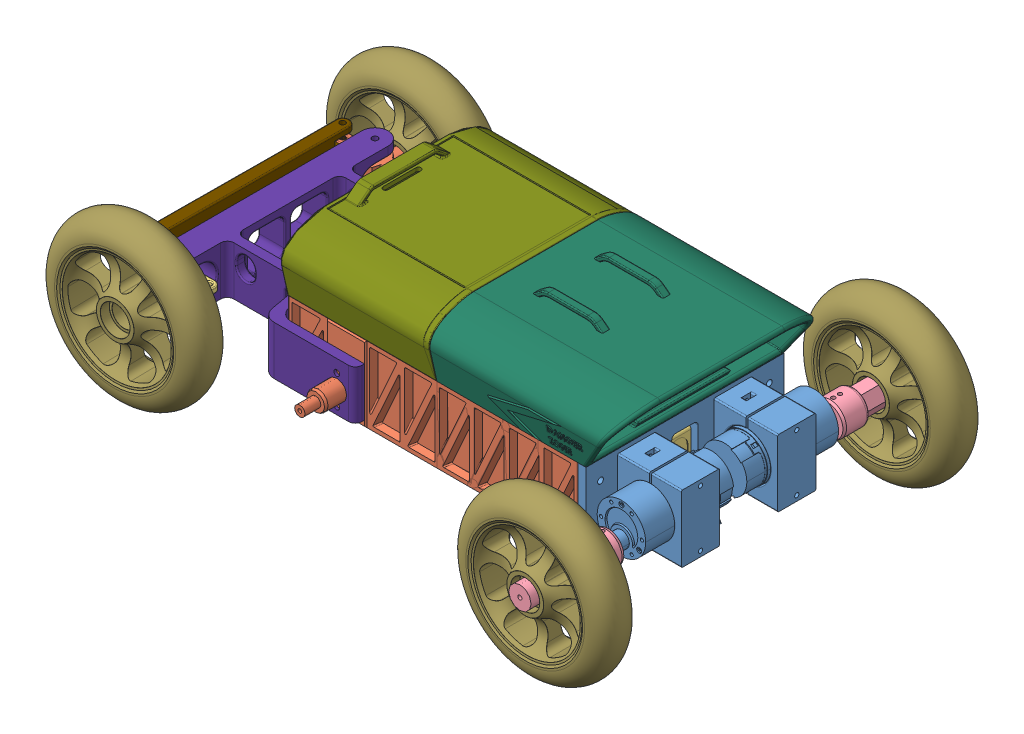
SolidWorks assembly Assem1, configuration Default. Lengths in mm.
Overall size (495.08 171.35 292.11).
38 component instances, 24 part files, 59 mates.
Components (placement in the parent):
- 37D motor clamp-1: 37D motor clamp [Default] at (81 28.5 53.125) size (54.32 57 190.1)
- MainChasis-1: MainChasis [Default] at origin size (220.8 57 222)
- Turnigy_2200mAh_3S_20C_Lipo_Pack-1: Turnigy_2200mAh_3S_20C_Lipo_Pack [Valor predeterminado] at (19.2115 22 -12.0586) size (103 34 24)
- 17HexHub(3.2shaft)-1: 17HexHub(3.2shaft) [Default] at (100.925 21.5 83.05) x (1 0 0) z (0 -1 0) size (25 67 25)
- raspberryPi3B-1: raspberryPi3B [Detailed] at (-91 17 -32.5) x (1 0 0) z (0 1 0) size (87.05 58.5 18.55)
- BTS7960 43A HIGH POWER H BRIDGE MODULE-1: BTS7960 43A HIGH POWER H BRIDGE MODULE [Default] at (35 15 38.7) size (51 42.4 49.96)
  - PCB, BTS7960 43A HIGH POWER H BRIDGE MODULE-1: PCB, BTS7960 43A HIGH POWER H BRIDGE MODULE [Default] at origin size (49.5 1.7 49.8)
  - HEATSINK, BTS7960 43A HIGH POWER H BRIDGE MODULE-1: HEATSINK, BTS7960 43A HIGH POWER H BRIDGE MODULE [Default] at (0 0 2.4) size (51 23 32.02)
  - ALUMINUM ELECTROLYTIC CAPACITOR, 330 uF, BTS7960 43A HIGH POWER H BRIDGE MODULE-1: ALUMINUM ELECTROLYTIC CAPACITOR, 330 uF, BTS7960 43A HIGH POWER H BRIDGE MODULE [Default] at (-10.75 1.8 -19.85) x (0.999469 0 -0.032584) z (0.032584 0 0.999469) size (10.1 18.7 10.1)
  - 8 PIN HEADER, IC, BTS7960 43A HIGH POWER H BRIDGE MODULE-1: 8 PIN HEADER, IC, BTS7960 43A HIGH POWER H BRIDGE MODULE [Default] at (-34.78 4.2 20.29) x (0 0 -1) z (-1 0 0) size (5.08 11.6 10.16)
  - EUROSTYLE TERMINAL BLOCK 2 POS 5.0 MM RA PLUG, BTS7960 43A HIGH POWER H BRIDGE MODULE-1: EUROSTYLE TERMINAL BLOCK 2 POS 5.0 MM RA PLUG, BTS7960 43A HIGH POWER H BRIDGE MODULE [Default] at (0.75 4.2 -6.5) size (10 14.5 10.5)
  - EUROSTYLE TERMINAL BLOCK 2 POS 5.0 MM RA PLUG, BTS7960 43A HIGH POWER H BRIDGE MODULE-2: EUROSTYLE TERMINAL BLOCK 2 POS 5.0 MM RA PLUG, BTS7960 43A HIGH POWER H BRIDGE MODULE [Default] at (10.75 4.2 -6.5) size (10 14.5 10.5)
- BTS7960 43A HIGH POWER H BRIDGE MODULE-2: BTS7960 43A HIGH POWER H BRIDGE MODULE [Default] at (35 15 -41.3) size (51 42.4 49.96)
  - PCB, BTS7960 43A HIGH POWER H BRIDGE MODULE-1: PCB, BTS7960 43A HIGH POWER H BRIDGE MODULE [Default] at origin size (49.5 1.7 49.8)
  - HEATSINK, BTS7960 43A HIGH POWER H BRIDGE MODULE-1: HEATSINK, BTS7960 43A HIGH POWER H BRIDGE MODULE [Default] at (0 0 2.4) size (51 23 32.02)
  - ALUMINUM ELECTROLYTIC CAPACITOR, 330 uF, BTS7960 43A HIGH POWER H BRIDGE MODULE-1: ALUMINUM ELECTROLYTIC CAPACITOR, 330 uF, BTS7960 43A HIGH POWER H BRIDGE MODULE [Default] at (-10.75 1.8 -19.85) x (0.999469 0 -0.032584) z (0.032584 0 0.999469) size (10.1 18.7 10.1)
  - 8 PIN HEADER, IC, BTS7960 43A HIGH POWER H BRIDGE MODULE-1: 8 PIN HEADER, IC, BTS7960 43A HIGH POWER H BRIDGE MODULE [Default] at (-34.78 4.2 20.29) x (0 0 -1) z (-1 0 0) size (5.08 11.6 10.16)
  - EUROSTYLE TERMINAL BLOCK 2 POS 5.0 MM RA PLUG, BTS7960 43A HIGH POWER H BRIDGE MODULE-1: EUROSTYLE TERMINAL BLOCK 2 POS 5.0 MM RA PLUG, BTS7960 43A HIGH POWER H BRIDGE MODULE [Default] at (0.75 4.2 -6.5) size (10 14.5 10.5)
  - EUROSTYLE TERMINAL BLOCK 2 POS 5.0 MM RA PLUG, BTS7960 43A HIGH POWER H BRIDGE MODULE-2: EUROSTYLE TERMINAL BLOCK 2 POS 5.0 MM RA PLUG, BTS7960 43A HIGH POWER H BRIDGE MODULE [Default] at (10.75 4.2 -6.5) size (10 14.5 10.5)
- ArduinoMega-1: ArduinoMega [Default] at (-91.5092 16.651 32.4881) x (0.999999 0 0.00146) z (0 -1 0) size (107.95 53.42 12.95)
- Breadboard^Assem1-1: Breadboard^Assem1 [Default] at (26.7945 10.25 259.5004) x (0 0 -1) z (1 0 0) size (165.5 9.51 56.25) (hidden, virtual)
- SCOOTER WHEEL 120mm 7Rays-1: SCOOTER WHEEL 120mm 7Rays [Default] at (100.925 21.5 131.05) x (0 0 1) z (0.712554 -0.701617 0) size (30.01 120 120)
- SCOOTER WHEEL 120mm 7Rays-2: SCOOTER WHEEL 120mm 7Rays [Default] at (-234.3672 22.1 106.9935) x (0.020413 0 0.999792) z (-0.283759 -0.958878 0.005794) size (30.01 120 120)
- Lid-1: Lid [Default] at (19.5 90 0) x (1 0 0) z (0 0 -1) size (113 40 150) (hidden)
- F9.STEP-1: F9.STEP [Default] at (24.2544 92.7094 -32.1983) x (0 0 -1) z (-1 0 0) size (94.4 26.59 93.93)
  - F9 body.STEP-1: F9 body.STEP [Default] at (-78.1983 5.7094 50.7544) size (92.01 26.59 92.01)
  - F9 fan.STEP-1: F9 fan.STEP [Default] at (-74.2115 10.4094 -44.9134) x (-0.083202 0 0.996533) z (-0.996533 0 -0.083202) size (86.56 20 87.5)
- CoolingDuct-1: CoolingDuct [Default] at (19.5 57 0) size (144.49 58 165.73)
- FrontLib-1: FrontLib [Default] at (-93.7 57 0.2) size (116.29 53 165.02)
- AckermanSteering-MainStructure-1: AckermanSteering-MainStructure [Default] at origin size (154 37 172)
- AckermanSteering-Linkage-1: AckermanSteering-Linkage [Default] at (-0.5003 0.6 2.2164) x (0.999978 0 0.006581) z (-0.006581 0 0.999978) size (10 15 162)
- AckermanSteering-Servo Mount-1: AckermanSteering-Servo Mount [Default] at (1.3 5.2 0.4) size (30.4 14 77.2)
- AckermanSteering-WheelShaft-1: AckermanSteering-WheelShaft [Default] at (1.5727 -3.3471 -5.0466) x (0.999771 0 -0.021401) z (0.021401 0 0.999771) size (58.1 24.2 44.8)
- AckermanSteering-WheelShaft 2-1: AckermanSteering-WheelShaft 2 [Default] at (-1.6004 0.6 -4.7813) x (0.999792 0 -0.020413) z (0.020413 0 0.999792) size (60.1 24.41 47)
- DS3218MG MS24 Digital Servo 270-1: DS3218MG MS24 Digital Servo 270 [Default] at (-178.7888 12.2 -9.4) size (20.1 45.99 55.6)
- SCOOTER WHEEL 120mm 7Rays-5: SCOOTER WHEEL 120mm 7Rays [Default] at (-235.6634 18.1529 -106.9929) x (-0.021401 0 -0.999771) z (0.029352 -0.999569 -0.000628) size (30.01 120 120)
- SCOOTER WHEEL 120mm 7Rays-6: SCOOTER WHEEL 120mm 7Rays [Default] at (101.0039 21.5 -131.05) x (0 0 1) z (0.712554 -0.701617 0) size (30.01 120 120)
- 17HexHub(3.2shaft)-3: 17HexHub(3.2shaft) [Default] at (101.0039 21.5 -83.05) x (-1 0 0) z (0 -1 0) size (25 67 25)
Mates (geometry in assembly coordinates):
- Coincident2: coincident anti-aligned: plane of 37D motor clamp-1 through (70 28.5 53.125) normal (-1 0 0); plane of MainChasis-1 through (70 5 0) normal (1 0 0)
- Parallel6: parallel aligned: line of 37D motor clamp-1 through (70 0 75) axis (0 1 0); line of MainChasis-1 through (69.2 0 75) axis (0 1 0)
- Concentric1: concentric aligned: circle of 37D motor clamp-1; circle of 17HexHub(3.2shaft)-1
- Coincident8: coincident anti-aligned: plane of 17HexHub(3.2shaft)-1 through (100.925 23.9 135.05) normal (0 -1 0); plane of 37D motor clamp-1 through (100.925 23.9 83.05) normal (0 1 0)
- Coincident11: coincident anti-aligned: plane of 37D motor clamp-1 through (100.925 28.5 83.05) normal (0 0 1); plane of 17HexHub(3.2shaft)-1 through (100.925 21.5 83.05) normal (0 0 -1)
- Coincident12: coincident anti-aligned: plane of MainChasis-1 through (0 5 0) normal (0 1 0); plane of Turnigy_2200mAh_3S_20C_Lipo_Pack-1 through (-32.2885 5 11.9414) normal (0 -1 0)
- Parallel5: parallel anti-aligned: plane of MainChasis-1 through (0 5 0) normal (0 1 0); plane of raspberryPi3B-1 through (-91 16 -32.5) normal (0 -1 0)
- Coincident17: coincident anti-aligned: plane of MainChasis-1 through (0 5 0) normal (0 1 0); plane of BTS7960 43A HIGH POWER H BRIDGE MODULE-3/HEATSINK, BTS7960 43A HIGH POWER H BRIDGE MODULE-1 through (50.3575 5 118.4979) normal (0 -1 0)
- Coincident23: coincident anti-aligned: plane of MainChasis-1 through (0 5 0) normal (0 1 0); plane of Breadboard^Assem1-1 through (26.7945 5 259.5004) normal (0 -1 0)
- Coincident24: coincident anti-aligned: line of 37D motor clamp-1 through (70 57 -75) axis (0 0 1); line of MainChasis-1 through (70 57 74.2) axis (0 0 -1)
- Concentric2: concentric anti-aligned: circle of ArduinoMega-1; circle of MainChasis-1
- Coincident26: coincident anti-aligned: plane of MainChasis-1 through (0 15 0) normal (0 1 0); plane of ArduinoMega-1 through (-40.6702 15 5.8542) normal (0 -1 0)
- Coincident28: coincident anti-aligned: plane of MainChasis-1 through (0 15 0) normal (0 1 0); plane of raspberryPi3B-1 through (-91 15 -32.5) normal (0 -1 0)
- Concentric4: concentric anti-aligned: circle of MainChasis-1; circle of raspberryPi3B-1
- Concentric5: concentric aligned: circle of MainChasis-1; circle of raspberryPi3B-1
- Coincident29: coincident anti-aligned: plane of MainChasis-1 through (-80 15 0) normal (0 1 0); plane of BTS7960 43A HIGH POWER H BRIDGE MODULE-1/PCB, BTS7960 43A HIGH POWER H BRIDGE MODULE-1 through (35 15 38.7) normal (0 -1 0)
- Concentric6: concentric anti-aligned: cylinder of MainChasis-1 through (55 15 20) axis (0 -1 0) radius 1.5; cylinder of BTS7960 43A HIGH POWER H BRIDGE MODULE-1/PCB, BTS7960 43A HIGH POWER H BRIDGE MODULE-1 through (55 16.7 20) axis (0 1 0) radius 1.6
- Concentric7: concentric anti-aligned: cylinder of MainChasis-1 through (15 15 60) axis (0 -1 0) radius 1.5; cylinder of BTS7960 43A HIGH POWER H BRIDGE MODULE-1/PCB, BTS7960 43A HIGH POWER H BRIDGE MODULE-1 through (15 16.7 60) axis (0 1 0) radius 1.6
- Coincident30: coincident anti-aligned: plane of MainChasis-1 through (-80 15 0) normal (0 1 0); plane of BTS7960 43A HIGH POWER H BRIDGE MODULE-2/PCB, BTS7960 43A HIGH POWER H BRIDGE MODULE-1 through (35 15 -41.3) normal (0 -1 0)
- Concentric8: concentric anti-aligned: cylinder of MainChasis-1 through (55 15 -60) axis (0 -1 0) radius 1.5; cylinder of BTS7960 43A HIGH POWER H BRIDGE MODULE-2/PCB, BTS7960 43A HIGH POWER H BRIDGE MODULE-1 through (55 16.7 -60) axis (0 1 0) radius 1.6
- Concentric9: concentric anti-aligned: cylinder of MainChasis-1 through (15 15 -20) axis (0 -1 0) radius 1.5; cylinder of BTS7960 43A HIGH POWER H BRIDGE MODULE-2/PCB, BTS7960 43A HIGH POWER H BRIDGE MODULE-1 through (15 16.7 -20) axis (0 1 0) radius 1.6
- Coincident31: coincident anti-aligned: plane of 17HexHub(3.2shaft)-1 through (100.925 21.5 123.05) normal (0 0 1); plane of SCOOTER WHEEL 120mm 7Rays-1 through (93.2072 13.6619 123.05) normal (0 0 -1)
- Concentric10: concentric aligned: cylinder of 17HexHub(3.2shaft)-1 through (100.925 21.5 135.05) axis (0 0 -1) radius 5.95; cylinder of SCOOTER WHEEL 120mm 7Rays-1 through (100.925 21.5 117.05) axis (0 0 -1) radius 9
- Coincident34: coincident aligned: plane of 37D motor clamp-1 through (70 28.5 75) normal (0 0 1); plane of MainChasis-1 through (-80 5 75) normal (0 0 1)
- Coincident35: coincident anti-aligned: plane of MainChasis-1 through (-80 57 0) normal (0 1 0); plane of Lid-1 through (19.5 57 0) normal (0 -1 0)
- Coincident40: coincident anti-aligned: plane of F9.STEP-1/F9 body.STEP-1 through (60.5 87 -41) normal (0 1 0); plane of Lid-1 through (19.5 87 0) normal (0 -1 0)
- Concentric16: concentric aligned: circle of Lid-1; circle of F9.STEP-1/F9 body.STEP-1
- Parallel7: parallel aligned: plane of Lid-1 through (19.5 87 75) normal (0 0 1); plane of F9.STEP-1/F9 body.STEP-1 through (19.5 62 46) normal (0 0 1)
- Coincident42: coincident aligned: plane of 37D motor clamp-1 through (76 28.5 53.125) normal (1 0 0); plane of Lid-1 through (76 87 0) normal (1 0 0)
- Coincident44: coincident aligned: plane of MainChasis-1 through (-80 5 75) normal (0 0 1); plane of Lid-1 through (19.5 87 75) normal (0 0 1)
- Coincident48: coincident anti-aligned: plane of MainChasis-1 through (0 57 0) normal (0 1 0); plane of FrontLib-1 through (-93.7 57 0.2) normal (0 -1 0)
- Coincident49: coincident anti-aligned: plane of MainChasis-1 through (-80 57 0) normal (0 1 0); plane of CoolingDuct-1 through (19.5 57 0) normal (0 -1 0)
- Coincident50: coincident anti-aligned: plane of 37D motor clamp-1 through (70 28.5 53.125) normal (-1 0 0); plane of CoolingDuct-1 through (70 50 0) normal (1 0 0)
- Coincident51: coincident anti-aligned: plane of MainChasis-1 through (-225 57 70) normal (0 0 -1); plane of CoolingDuct-1 through (19.5 50 70) normal (0 0 1)
- Coincident52: coincident aligned: circle of MainChasis-1; circle of AckermanSteering-MainStructure-1
- Concentric17: concentric aligned: cylinder of MainChasis-1 through (-105 32.5 -76) axis (0 0 1) radius 2.2; cylinder of AckermanSteering-MainStructure-1 through (-105 32.5 -76) axis (0 0 1) radius 2.2
- Concentric18: concentric anti-aligned: cylinder of AckermanSteering-MainStructure-1 through (-235 40 76) axis (0 -1 0) radius 2.2; cylinder of AckermanSteering-WheelShaft 2-1 through (-235 0.6 76) axis (0 1 0) radius 2.3
- Concentric19: concentric anti-aligned: cylinder of AckermanSteering-MainStructure-1 through (-235 40 -76) axis (0 -1 0) radius 2.2; cylinder of AckermanSteering-WheelShaft-1 through (-235 59.3715 -76) axis (0 1 0) radius 2.2
- Coincident54: coincident: plane of AckermanSteering-MainStructure-1 through (-210 35 0) normal (0 -1 0); plane of AckermanSteering-WheelShaft-1 through (-251.1946 35 2.3501) normal (0 1 0)
- Coincident55: coincident anti-aligned: plane of AckermanSteering-Linkage-1 through (-259.9948 30.6 76.5103) normal (0 1 0); plane of AckermanSteering-WheelShaft 2-1 through (-1.6004 30.6 -4.7813) normal (0 -1 0)
- Concentric20: concentric anti-aligned: cylinder of AckermanSteering-Linkage-1 through (-259.9948 25.6 76.5103) axis (0 1 0) radius 2.1; cylinder of AckermanSteering-WheelShaft 2-1 through (-259.9948 97.9592 76.5103) axis (0 -1 0) radius 2.1
- Concentric21: concentric anti-aligned: cylinder of AckermanSteering-Linkage-1 through (-258.9945 25.6 -75.4864) axis (0 1 0) radius 2.1; cylinder of AckermanSteering-WheelShaft-1 through (-258.9945 90.6414 -75.4864) axis (0 -1 0) radius 2.1
- Coincident57: coincident anti-aligned: plane of AckermanSteering-Servo Mount-1 through (-168.7888 12.2 0.4) normal (-1 0 0); plane of DS3218MG MS24 Digital Servo 270-1 through (-168.7888 -7.8 -19.4) normal (1 0 0)
- Coincident58: coincident anti-aligned: plane of AckermanSteering-Servo Mount-1 through (1.3 12.2 20.6) normal (0 0 -1); plane of DS3218MG MS24 Digital Servo 270-1 through (-188.7888 -7.8 20.6) normal (0 0 1)
- Coincident59: coincident anti-aligned: plane of AckermanSteering-Servo Mount-1 through (1.3 12.2 0.4) normal (0 1 0); plane of DS3218MG MS24 Digital Servo 270-1 through (-169.7888 12.2 17.6) normal (0 -1 0)
- Concentric22: concentric aligned: cylinder of SCOOTER WHEEL 120mm 7Rays-2 through (-234.653 22.1 92.9965) axis (-0.020413 0 -0.999792) radius 9; cylinder of AckermanSteering-WheelShaft 2-1 through (-234.2855 22.1 110.9927) axis (-0.020413 0 -0.999792) radius 3.95
- Coincident65: coincident anti-aligned: plane of SCOOTER WHEEL 120mm 7Rays-2 through (-245.076 25.222 99.2105) normal (-0.020413 0 -0.999792); plane of AckermanSteering-WheelShaft 2-1 through (-129.5524 0.6 96.8518) normal (0.020413 0 0.999792)
- Coincident66: coincident anti-aligned: plane of AckermanSteering-MainStructure-1 through (0 40 39) normal (0 0 -1); plane of AckermanSteering-Servo Mount-1 through (1.3 19.2 39) normal (0 0 1)
- Tangent1: tangent anti-aligned: plane of AckermanSteering-MainStructure-1 through (-176.7888 15 -86) normal (-1 0 0); cylinder of AckermanSteering-Servo Mount-1 through (-178.9888 16.1 -38.2) axis (0 0 1) radius 2.2
- Coincident69: coincident anti-aligned: plane of AckermanSteering-WheelShaft 2-1 through (-1.6004 30.6 -4.7813) normal (0 -1 0); plane of DS3218MG MS24 Digital Servo 270-1 through (-178.7888 30.6 -9.4) normal (0 1 0)
- Concentric24: concentric aligned: cylinder of AckermanSteering-WheelShaft-1 through (-235.749 18.1529 -110.992) axis (0.021401 0 0.999771) radius 3.95; cylinder of SCOOTER WHEEL 120mm 7Rays-5 through (-235.3638 18.1529 -92.9961) axis (0.021401 0 0.999771) radius 11
- Coincident70: coincident anti-aligned: plane of AckermanSteering-WheelShaft-1 through (-130.5163 -3.3471 -101.2418) normal (-0.021401 0 -0.999771); plane of SCOOTER WHEEL 120mm 7Rays-5 through (-224.4995 18.4758 -99.23) normal (0.021401 0 0.999771)
- Concentric26: concentric anti-aligned: cylinder of SCOOTER WHEEL 120mm 7Rays-6 through (101.0039 21.5 -145.05) axis (0 0 -1) radius 11; cylinder of 17HexHub(3.2shaft)-3 through (101.0039 21.5 -135.05) axis (0 0 1) radius 5.95
- Coincident71: coincident anti-aligned: plane of SCOOTER WHEEL 120mm 7Rays-6 through (93.2861 13.6619 -123.05) normal (0 0 1); plane of 17HexHub(3.2shaft)-3 through (101.0039 21.5 -123.05) normal (0 0 -1)
- Concentric27: concentric aligned: cylinder of 37D motor clamp-1 through (101.0039 21.5 -95.05) axis (0 0 1) radius 3; cylinder of 17HexHub(3.2shaft)-3 through (101.0039 21.5 -135.05) axis (0 0 1) radius 3
- Coincident72: coincident anti-aligned: plane of 37D motor clamp-1 through (101.0039 23.9 -83.05) normal (0 1 0); plane of 17HexHub(3.2shaft)-3 through (101.0039 23.9 -135.05) normal (0 -1 0)
- Coincident73: coincident anti-aligned: plane of 37D motor clamp-1 through (101.0039 28.5 -83.05) normal (0 0 -1); plane of 17HexHub(3.2shaft)-3 through (101.0039 21.5 -83.05) normal (0 0 1)
- Coincident74: coincident anti-aligned: plane of AckermanSteering-MainStructure-1 through (-210 35 0) normal (0 -1 0); plane of AckermanSteering-WheelShaft 2-1 through (-211.5566 35 -0.4945) normal (0 1 0)
- Concentric28: concentric aligned: cylinder of AckermanSteering-Linkage-1 through (-258.9945 82.1 -75.4864) axis (0 -1 0) radius 2.1; cylinder of AckermanSteering-WheelShaft-1 through (-258.9945 90.6414 -75.4864) axis (0 -1 0) radius 2.1
